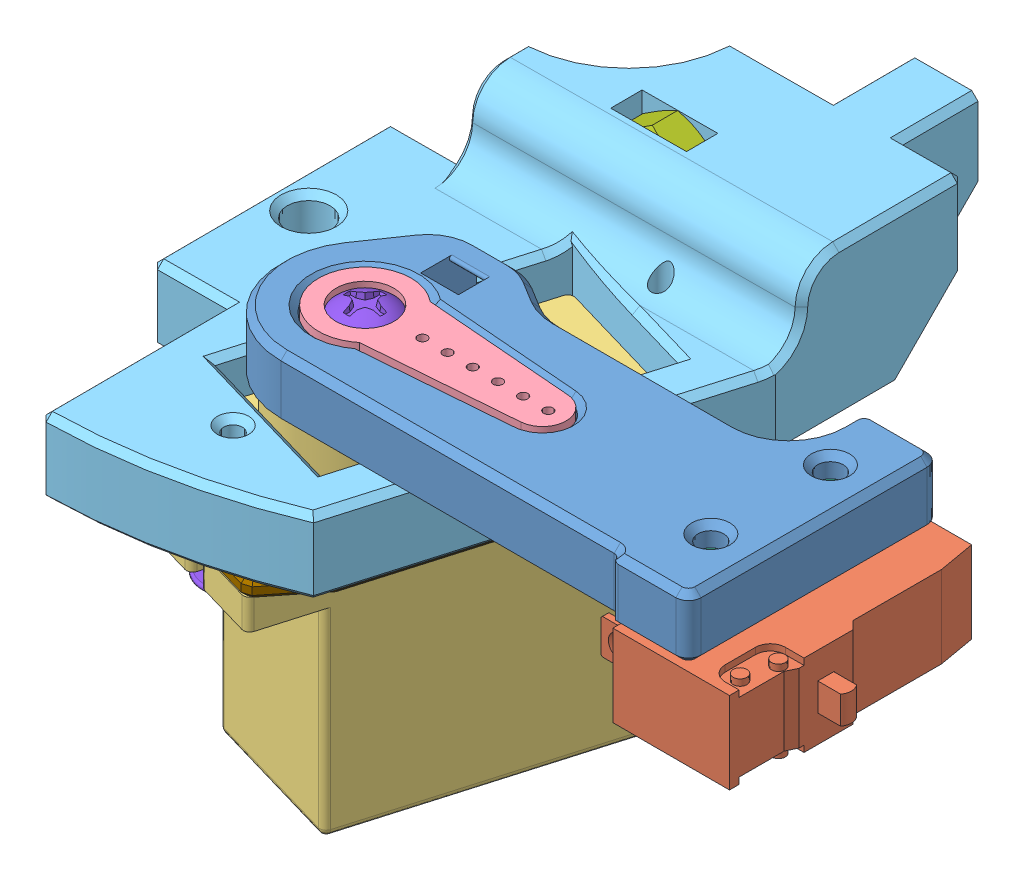
SolidWorks assembly ServoProbeAssembly, configuration e3dV6. Lengths in mm.
Overall size (56.04 32.57 53.15).
12 component instances, 9 part files, 28 mates.
Components (placement in the parent):
- ZProbeArm-e3dv6-1: ZProbeArm-e3dv6 [DefaultMirror] at (-4.5638 -41.7304 28.053) x (1 0 0.000181) z (-0.000181 0 1) size (39.66 4.95 19.95)
- SnapLimitSwitch-1: SnapLimitSwitch [Default] at (24.4015 -36.4147 11.5558) x (0.000181 0 -1) z (0 -1 0) size (19.99 14.86 6.5)
- Servo-HXT900-1: Servo-HXT900 [Default] at (3.7992 -59.2135 5.9689) x (0.280139 0 -0.959959) z (0 1 0) size (32.3 12 29.6)
- Servo Horn-1: Servo Horn [Default] at (29.6923 -29.8135 24.1326) size (19.66 4.12 7.35)
- ServoShelfBracket-1: ServoShelfBracket [HXT900] at (-13.9503 -39.6135 -18.0479) x (0.004648 0 0.999989) z (0 -1 0) size (53 32.5 12)
- M2.5x10HexSocketScrew-1: M2.5x10HexSocketScrew [91292A014] at (26.7629 -29.6659 16.1282) x (1 0 0) z (0 1 0) size (4.5 4.5 13.01)
- M3HexNut-1: M3HexNut [90591A121] at (-2.9123 -30.6135 -9.8991) x (0.499995 -0.866025 -0.002324) z (-0.866016 -0.5 0.004025) size (5.5 2.58 6.35)
- ServoScrew-1: ServoScrew [93406A071] at (-2.7203 -29.1235 14.1229) x (1 0 0) z (0 1 0) size (4.93 5.18 10.49)
- M2.5x10HexSocketScrew-2: M2.5x10HexSocketScrew [91292A014] at (26.7646 -29.6659 6.6282) x (1 0 0) z (0 1 0) size (4.5 4.5 13.01)
- ServoScrew-2: ServoScrew [93406A071] at (-5.0875 -43.4135 22.2345) x (1 0 0) z (0 -1 0) size (4.93 5.18 10.49)
- ServoScrew-3: ServoScrew [93406A071] at (2.5884 -43.4135 -4.0684) x (1 0 0) z (0 -1 0) size (4.93 5.18 10.49)
- ServoSpacer-1: ServoSpacer [Default] at (3.7992 -41.0135 5.9689) x (0.280139 0 -0.959959) z (0 1 0) size (32.7 16.4 1.4)
Mates (geometry in assembly coordinates):
- Concentric14: concentric anti-aligned: cylinder of Servo Horn-1 through (-2.7203 -28.1935 14.1229) axis (0 -1 0) radius 3.675; cylinder of ZProbeArm-e3dv6-1 through (-2.7203 -29.8135 14.1229) axis (0 1 0) radius 3.775
- Coincident23: coincident anti-aligned: plane of Servo Horn-1 through (-2.7203 -29.8135 14.1229) normal (0 -1 0); plane of ZProbeArm-e3dv6-1 through (-2.7203 -29.8135 14.1229) normal (0 1 0)
- Concentric15: concentric anti-aligned: cylinder of Servo Horn-1 through (5.846 -27.1329 14.1236) axis (0 -1 0) radius 0.375; cylinder of ZProbeArm-e3dv6-1 through (5.846 -33.1635 14.1236) axis (0 1 0) radius 1.025
- Concentric16: concentric aligned: cylinder of SnapLimitSwitch-1 through (26.7629 -39.6659 16.1282) axis (0 1 0) radius 1.1049; cylinder of ZProbeArm-e3dv6-1 through (26.7629 -33.1635 16.1282) axis (0 1 0) radius 1.025
- Coincident24: coincident anti-aligned: plane of SnapLimitSwitch-1 through (24.4033 -33.1635 1.5609) normal (0 1 0); plane of ZProbeArm-e3dv6-1 through (-4.5638 -33.1635 28.053) normal (0 -1 0)
- Parallel3: parallel anti-aligned: plane of SnapLimitSwitch-1 through (24.3997 -39.6659 21.5507) normal (-1 0 -0.000181); plane of ZProbeArm-e3dv6-1 through (30.2607 -33.1635 28.0593) normal (1 0 0.000181)
- Concentric5: concentric aligned: cylinder of Servo Horn-1 through (-2.7203 -29.6135 14.1229) axis (0 -1 0) radius 2.3; cylinder of Servo-HXT900-1 through (-2.7203 -29.6135 14.1229) axis (0 -1 0) radius 2.3
- Coincident16: coincident anti-aligned: plane of Servo Horn-1 through (-2.7203 -29.6135 14.1229) normal (0 -1 0); plane of Servo-HXT900-1 through (-2.7203 -29.6135 14.1229) normal (0 1 0)
- Distance1: distance = 1.4 mm anti-aligned: plane of ServoShelfBracket-1 through (-13.9503 -39.6135 -18.0479) normal (0 -1 0); plane of Servo-HXT900-1 through (-11.5336 -41.0135 22.9056) normal (0 1 0)
- Concentric19: concentric anti-aligned: cylinder of Servo-HXT900-1 through (-5.0875 -59.2145 22.2345) axis (0 1 0) radius 1; cylinder of ServoShelfBracket-1 through (-5.0875 -27.6125 22.2345) axis (0 -1 0) radius 0.75
- Concentric20: concentric anti-aligned: cylinder of ServoShelfBracket-1 through (2.5884 -27.6125 -4.0684) axis (0 -1 0) radius 0.75; cylinder of Servo-HXT900-1 through (2.5884 -59.2145 -4.0684) axis (0 1 0) radius 1
- Concentric21: concentric aligned: cylinder of ZProbeArm-e3dv6-1 through (26.7646 -33.1635 6.6282) axis (0 1 0) radius 1.025; cylinder of M2.5x10HexSocketScrew-2 through (26.7646 -42.1659 6.6282) axis (0 1 0) radius 2.25
- Concentric22: concentric aligned: cylinder of ZProbeArm-e3dv6-1 through (26.7629 -33.1635 16.1282) axis (0 1 0) radius 1.025; cylinder of M2.5x10HexSocketScrew-1 through (26.7629 -42.1659 16.1282) axis (0 1 0) radius 2.25
- Coincident27: coincident anti-aligned: plane of SnapLimitSwitch-1 through (24.4033 -39.6659 1.5609) normal (0 -1 0); plane of M2.5x10HexSocketScrew-1 through (26.7629 -39.6659 16.1282) normal (0 1 0)
- Coincident28: coincident anti-aligned: plane of SnapLimitSwitch-1 through (24.4033 -39.6659 1.5609) normal (0 -1 0); plane of M2.5x10HexSocketScrew-2 through (26.7646 -39.6659 6.6282) normal (0 1 0)
- Concentric23: concentric anti-aligned: cylinder of Servo-HXT900-1 through (-2.7203 -36.6135 14.1229) axis (0 1 0) radius 0.8; cylinder of ServoScrew-1 through (-2.7203 -29.6156 14.1229) axis (0 -1 0) radius 1.0922
- Coincident29: coincident anti-aligned: plane of Servo Horn-1 through (-2.7203 -29.1235 14.1229) normal (0 1 0); plane of ServoScrew-1 through (-2.7203 -29.1235 14.1229) normal (0 -1 0)
- Concentric24: concentric anti-aligned: cylinder of ServoShelfBracket-1 through (2.5884 -27.6125 -4.0684) axis (0 -1 0) radius 0.75; cylinder of ServoScrew-3 through (2.5884 -42.9214 -4.0684) axis (0 1 0) radius 1.0922
- Concentric25: concentric anti-aligned: cylinder of ServoShelfBracket-1 through (-5.0875 -27.6125 22.2345) axis (0 -1 0) radius 0.75; cylinder of ServoScrew-2 through (-5.0875 -42.9214 22.2345) axis (0 1 0) radius 1.0922
- Coincident30: coincident anti-aligned: plane of Servo-HXT900-1 through (-11.5336 -43.4135 22.9056) normal (0 -1 0); plane of ServoScrew-3 through (2.5884 -43.4135 -4.0684) normal (0 1 0)
- Coincident31: coincident anti-aligned: plane of Servo-HXT900-1 through (-11.5336 -43.4135 22.9056) normal (0 -1 0); plane of ServoScrew-2 through (-5.0875 -43.4135 22.2345) normal (0 1 0)
- Coincident32: coincident anti-aligned: plane of ServoShelfBracket-1 through (-5.9179 -27.6125 -11.0852) normal (0.004648 0 0.999989); plane of M3HexNut-1 through (-0.1679 -32.2012 -11.1119) normal (-0.004648 0 -0.999989)
- Concentric26: concentric aligned: cylinder of ServoShelfBracket-1 through (-2.8947 -30.6135 -6.0992) axis (-0.004648 0 -0.999989) radius 1.7; circle of M3HexNut-1
- Parallel4: parallel anti-aligned: plane of ServoShelfBracket-1 through (-5.9179 -27.6125 -11.0852) normal (0.999989 0 -0.004648); plane of M3HexNut-1 through (-5.6567 -29.0258 -8.6864) normal (-0.999989 0 0.004648)
- InPlace1: in place: plane of Servo-HXT900-1 through (-11.5336 -41.0135 22.9056) normal (0 1 0); plane of ? through (0 -41.0135 0) normal (0 1 0); moOrthogonalPlaneRef_w of Servo-HXT900-1 through (-11.5336 -41.0135 22.9056) normal (0 1 0); plane of ? through (0 -41.0135 0) normal (0 0 -1); plane of Servo-HXT900-1 through (-11.5336 -41.0135 22.9056) normal (0 1 0); unknown of ?; plane of Servo-HXT900-1 through (-11.5336 -41.0135 22.9056) normal (0 1 0); unknown of ServoSpacer-1
- Coincident33: coincident aligned: plane of Servo-HXT900-1; plane of ServoSpacer-1
- Coincident34: coincident aligned: moOrthogonalPlaneRef_w of Servo-HXT900-1 through (3.7992 -41.0135 5.9689) normal (-0.959959 0 -0.280139); plane of ServoSpacer-1
- Coincident35: coincident anti-aligned: moOrthogonalPlaneRef_w of Servo-HXT900-1 through (3.7992 -41.0135 5.9689) normal (-0.280139 0 0.959959); plane of ServoSpacer-1
